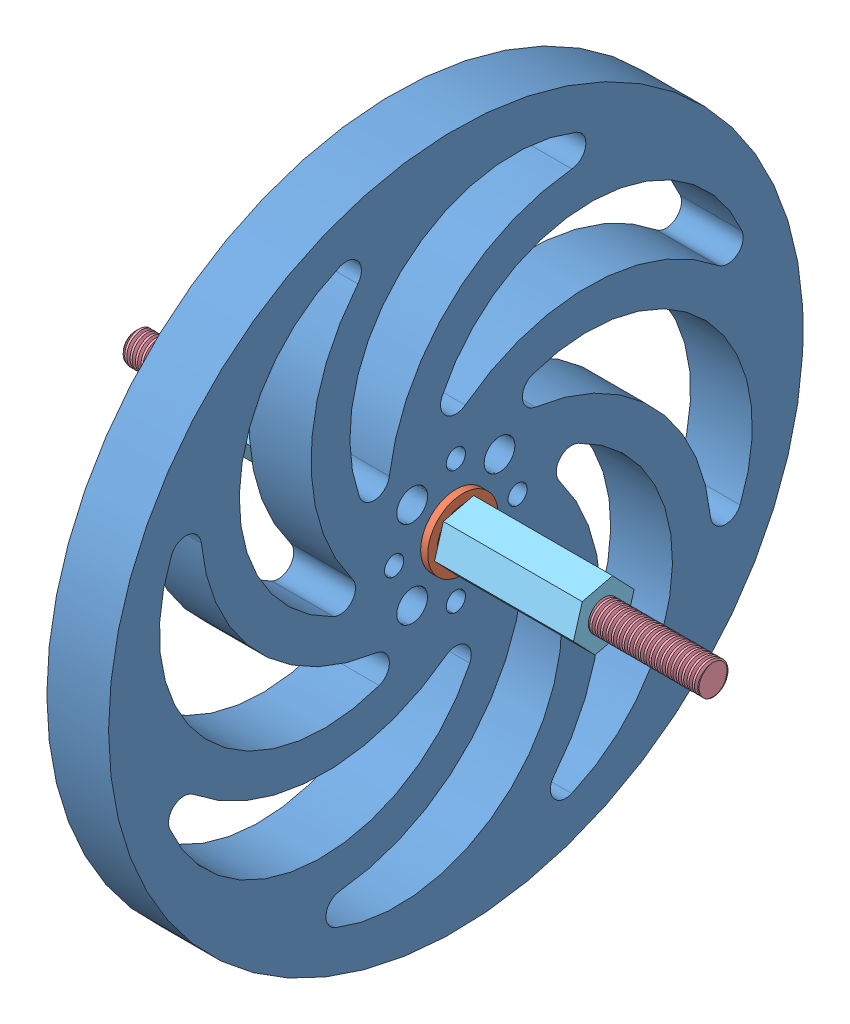
SolidWorks assembly Laser_Sprocket-Passive, configuration Default. Lengths in mm.
Overall size (75.82 90 90).
14 component instances, 8 part files, 47 mates.
Components (placement in the parent):
- Laser-Sprocket_Center-Passive-1: Laser-Sprocket_Center-Passive [Default] at (26.0533 23.785 47.0741) size (8 90 90)
- MotorHub-1: MotorHub [Default] at (21.5533 23.785 47.0741) x (0 -1 0) z (0 0 -1) (suppressed, hidden)
- MotorHub-2: MotorHub [Default] at (38.5533 23.785 47.0741) x (0 1 0) z (0 0 -1) (suppressed, hidden)
- Laser-Sprocket_Side-Passive-1: Laser-Sprocket_Side-Passive [Default] at (34.0533 23.785 47.0741) x (1 0 0) z (0 0 -1) (suppressed, hidden)
- Laser-Sprocket_Side-Passive-2: Laser-Sprocket_Side-Passive [Default] at (18.0533 23.785 47.0741) x (1 0 0) z (0 0 -1) (suppressed, hidden)
- SprocketShaft-1: SprocketShaft [Default] at (-0.9467 23.785 47.0741) x (1 0 0) z (0 0.999918 0.012834) (suppressed, hidden)
- SprocketShaft-2: SprocketShaft [Default] at (43.0533 23.785 47.0741) x (1 0 0) z (0 0.984527 0.175231) (suppressed, hidden)
- Bearing-4mm-1: Bearing-4mm [Default] at (34.9674 23.785 47.0741) size (3.17 9.12 9.12)
- Bearing-4mm-2: Bearing-4mm [Default] at (25.1392 23.785 47.0741) x (-1 0 0) z (0 0 -1) size (3.17 9.12 9.12)
- msh_4-1: msh_4 [Default] at (35.0923 23.785 47.0741) x (0 0 -1) z (0 -1 0) size (4.59 0.25 5.77)
- msh_4-2: msh_4 [Default] at (25.0143 23.785 47.0741) x (0 1 0) z (0 0 1) size (4.59 0.25 5.77)
- Double-Threaded-Rod-M4-1: Double-Threaded-Rod-M4 [Default] at (67.5533 23.785 47.0741) x (0 0.990585 0.136901) z (0 -0.136901 0.990585) size (4.62 75.82 4.09)
- Hex-Spacer-18mm-M4-1: Hex-Spacer-18mm-M4 [Default] at (53.2173 54.426 69.0876) x (0 0.972067 0.234705) z (0 -0.234705 0.972067) size (7 18 8.08)
- Hex-Spacer-18mm-M4-2: Hex-Spacer-18mm-M4 [Default] at (24.8893 -5.0235 71.4368) x (0 -0.464207 0.885727) z (0 -0.885727 -0.464207) size (7 18 8.08)
Mates (geometry in assembly coordinates):
- Concentrico1: concentric aligned: circle of ?; circle of ?
- Coincidente2: coincident anti-aligned: plane of ? through (79.1863 24.8553 45.995) normal (1 0 0); plane of ? through (79.1863 24.8553 45.995) normal (-1 0 0)
- Concentrico2: concentric aligned: circle of ?; circle of ?
- Concentrico3: concentric aligned: circle of ?; circle of ?
- Coincidente5: coincident anti-aligned: plane of ? through (71.1863 24.8553 45.995) normal (-1 0 0); plane of ? through (71.1863 24.8553 45.995) normal (1 0 0)
- Concentrico4: concentric aligned: circle of ?; circle of ?
- Concentrico5: concentric aligned: circle of ?; circle of MotorHub-1
- Concentrico6: concentric aligned: circle of ?; circle of MotorHub-1
- Coincidente7: coincident anti-aligned: plane of ? through (63.1863 24.8553 45.995) normal (-1 0 0); plane of MotorHub-1 through (63.1863 35.8553 45.995) normal (1 0 0)
- Concentrico7: concentric anti-aligned: circle of ?; circle of MotorHub-2
- Concentrico8: concentric anti-aligned: circle of ?; circle of MotorHub-2
- Coincidente8: coincident anti-aligned: plane of ? through (87.1863 24.8553 45.995) normal (1 0 0); plane of MotorHub-2 through (87.1863 13.8553 45.995) normal (-1 0 0)
- Concentrico9: concentric aligned: circle of ?; circle of Laser-Sprocket_Side-Passive-1
- Concentrico10: concentric aligned: circle of ?; circle of Laser-Sprocket_Side-Passive-1
- Coincidente11: coincident anti-aligned: plane of ? through (79.1863 24.8553 45.995) normal (1 0 0); plane of Laser-Sprocket_Side-Passive-1 through (79.1863 24.8553 45.995) normal (-1 0 0)
- Concentrico11: concentric anti-aligned: circle of MotorHub-2; circle of Laser-Sprocket_Side-Passive-1
- Concentrico12: concentric anti-aligned: circle of MotorHub-2; circle of Laser-Sprocket_Side-Passive-1
- Coincidente12: coincident anti-aligned: plane of MotorHub-2 through (42.0533 34.785 47.0741) normal (-1 0 0); plane of Laser-Sprocket_Side-Passive-1 through (42.0533 23.785 47.0741) normal (1 0 0)
- Concentrico13: concentric aligned: circle of ?; circle of Laser-Sprocket_Side-Passive-2
- Concentrico14: concentric aligned: circle of ?; circle of Laser-Sprocket_Side-Passive-2
- Coincidente15: coincident anti-aligned: plane of ? through (71.1863 24.8553 45.995) normal (-1 0 0); plane of Laser-Sprocket_Side-Passive-2 through (71.1863 24.8553 45.995) normal (1 0 0)
- Concentrico15: concentric aligned: circle of MotorHub-1; circle of Laser-Sprocket_Side-Passive-2
- Concentrico16: concentric aligned: circle of MotorHub-1; circle of Laser-Sprocket_Side-Passive-2
- Coincidente16: coincident anti-aligned: plane of MotorHub-1 through (18.0533 12.785 47.0741) normal (1 0 0); plane of Laser-Sprocket_Side-Passive-2 through (18.0533 23.785 47.0741) normal (-1 0 0)
- Concentrico17: concentric anti-aligned: circle of MotorHub-1; circle of SprocketShaft-1
- Concentrico18: concentric aligned: circle of MotorHub-2; circle of SprocketShaft-2
- Coincidente19: coincident anti-aligned: plane of MotorHub-2 through (43.0533 25.785 47.0741) normal (1 0 0); plane of SprocketShaft-2 through (43.0533 23.785 47.0741) normal (-1 0 0)
- Coincidente20: coincident anti-aligned: plane of MotorHub-1 through (17.0533 21.785 47.0741) normal (-1 0 0); plane of SprocketShaft-1 through (17.0533 23.785 47.0741) normal (1 0 0)
- Coincidente21: coincident aligned: circle of Laser-Sprocket_Side-Passive-1; circle of Laser-Sprocket_Center-Passive-1
- Coincidente22: coincident aligned: circle of Laser-Sprocket_Side-Passive-2; circle of Laser-Sprocket_Center-Passive-1
- Concentrico19: concentric anti-aligned: circle of MotorHub-1; circle of MotorHub-2
- Concentrico20: concentric anti-aligned: circle of Laser-Sprocket_Center-Passive-1; circle of MotorHub-1
- Concentrico21: concentric anti-aligned: circle of Laser-Sprocket_Center-Passive-1; circle of Bearing-4mm-2
- Coincidente23: coincident anti-aligned: plane of Laser-Sprocket_Center-Passive-1 through (26.0533 23.785 47.0741) normal (-1 0 0); plane of Bearing-4mm-2 through (26.0533 28.3445 47.0741) normal (1 0 0)
- Coincidente24: coincident anti-aligned: plane of Laser-Sprocket_Center-Passive-1 through (34.0533 23.785 47.0741) normal (1 0 0); plane of Bearing-4mm-1 through (34.0533 28.3445 47.0741) normal (-1 0 0)
- Concentrico22: concentric aligned: circle of Laser-Sprocket_Center-Passive-1; circle of Bearing-4mm-1
- Concentrico23: concentric anti-aligned: circle of Bearing-4mm-2; circle of ?
- Coincidente25: coincident anti-aligned: plane of Bearing-4mm-1 through (34.9673 25.9351 47.0741) normal (1 0 0); plane of msh_4-1 through (34.9673 20.6168 47.5241) normal (-1 0 0)
- Concentrico24: concentric anti-aligned: circle of Bearing-4mm-1; circle of msh_4-1
- Concentrico25: concentric aligned: circle of ?; circle of msh_4-2
- Coincidente26: coincident anti-aligned: plane of Bearing-4mm-2 through (25.1393 25.9351 47.0741) normal (-1 0 0); plane of msh_4-2 through (25.1393 23.335 50.2423) normal (1 0 0)
- Concentrico26: concentric aligned: circle of Bearing-4mm-2; cone of Double-Threaded-Rod-M4-1 through (-7.4467 23.785 47.0741) axis (-1 0 0)
- Distanza2: distance = 33.5 mm aligned: plane of Double-Threaded-Rod-M4-1 through (-7.4467 23.785 47.0741) normal (-1 0 0); plane of Laser-Sprocket_Center-Passive-1 through (26.0533 23.785 47.0741) normal (-1 0 0)
- Concentrico27: concentric anti-aligned: circle of Bearing-4mm-1; circle of Hex-Spacer-18mm-M4-1
- Coincidente28: coincident anti-aligned: plane of msh_4-1 through (35.2173 20.6168 47.5241) normal (1 0 0); plane of Hex-Spacer-18mm-M4-1 through (35.2173 54.426 69.0876) normal (-1 0 0)
- Concentrico28: concentric aligned: circle of Bearing-4mm-2; circle of Hex-Spacer-18mm-M4-2
- Coincidente29: coincident anti-aligned: plane of msh_4-2 through (24.8893 23.335 50.2423) normal (-1 0 0); plane of Hex-Spacer-18mm-M4-2 through (24.8893 -5.0235 71.4368) normal (1 0 0)
